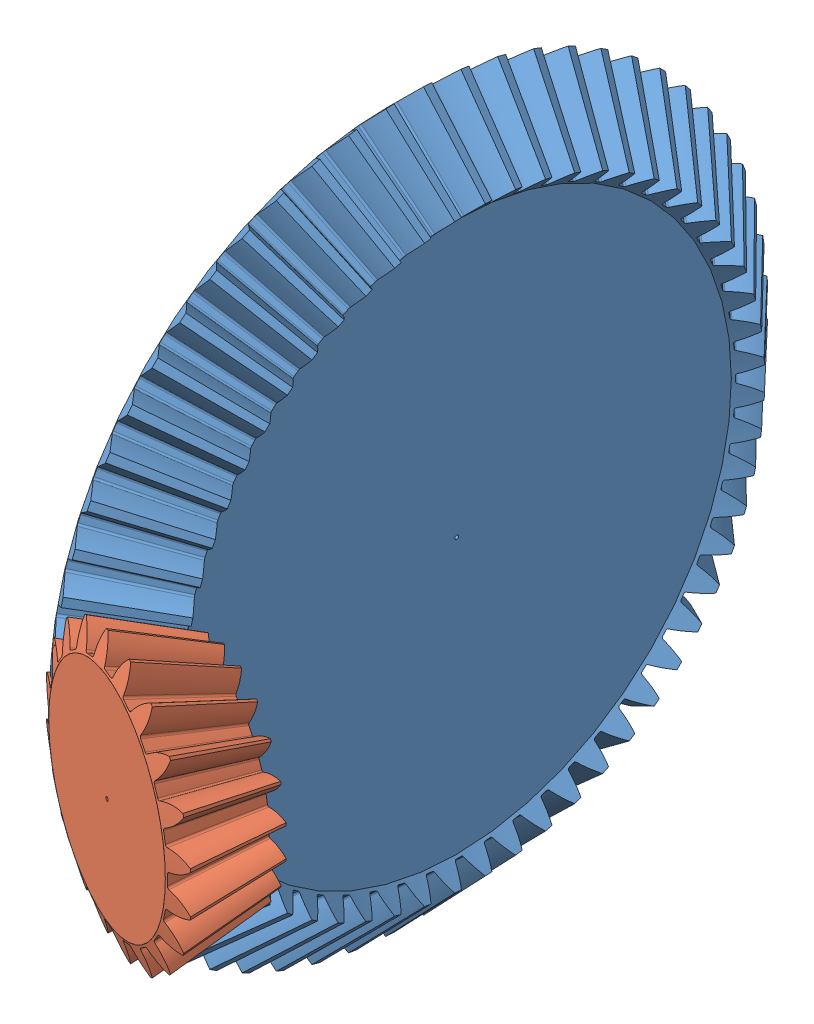
SolidWorks assembly Assem2, configuration Default. Lengths in mm.
Overall size (60.32 153.51 173.21).
2 component instances, 2 part files, 2 mates.
Components (placement in the parent):
- straight bevel gear_iso-1: straight bevel gear_iso [ISO - Straight bevel gear 2.5M 60GT 60PT 20PA 20FW ---60O10H50MD0.8N] at (-22.9759 -40.039 34.2643) size (19.18 153.51 153.51)
- straight bevel pinion_iso-1: straight bevel pinion_iso [ISO - Straight bevel pinion 2.5M20PT 60GT 14.5PA 20FW ---20O75H50MD0.8N] at (2.7521 -40.039 120.1258) x (0.376961 0 -0.926229) z (-0.926229 0 -0.376961) size (21.95 56.2 56.2)
Mates (geometry in assembly coordinates):
- Coincident2: coincident anti-aligned: plane of straight bevel gear_iso-1 through (-22.9759 -40.039 34.2643) normal (0 1 0); plane of straight bevel pinion_iso-1 through (2.7521 -40.039 120.1258) normal (0 -1 0)
- Angle2: planar angle = 1.95731 rad anti-aligned: plane of straight bevel pinion_iso-1 through (9.9779 -40.039 102.3713) normal (0.376961 0 -0.926229); plane of straight bevel gear_iso-1 through (-8.3386 -40.039 34.2643) normal (1 0 0)
